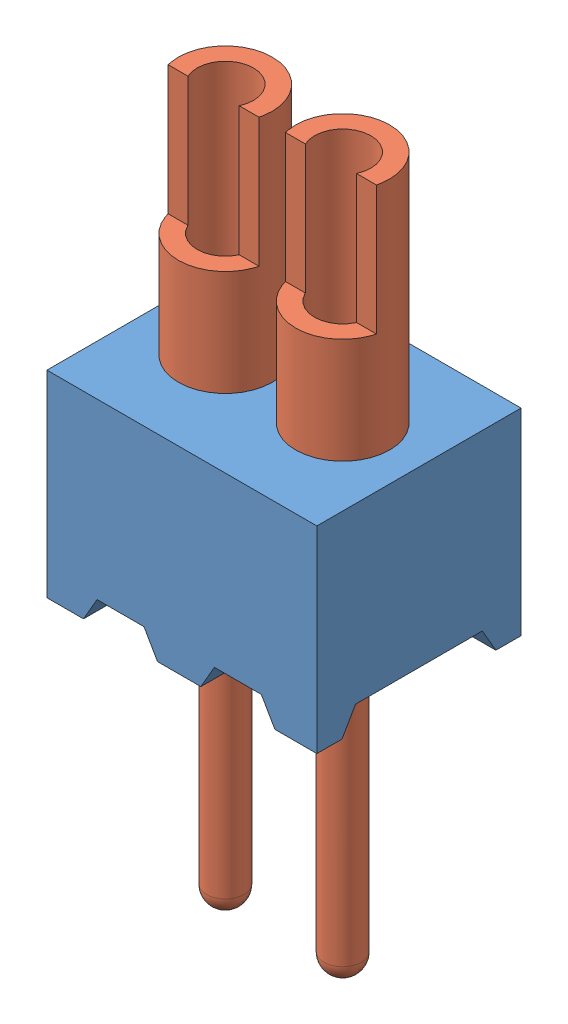
SolidWorks assembly mill-max-850-10-002-10-003000, configuration Default. Lengths in mm.
Overall size (2.92 7.7 2.21).
3 component instances, 2 part files, 0 mates.
Components (placement in the parent):
- mill-max-850-10-002-10-003000_P8XX-18-011-02-000000(P802-18-011-02-000000)-1: mill-max-850-10-002-10-003000_P8XX-18-011-02-000000(P802-18-011-02-000000) [Default] at origin size (2.92 2.13 2.21)
- mill-max-850-10-002-10-003000_3050(3050-0-01-15-00-00-03-0)-1: mill-max-850-10-002-10-003000_3050(3050-0-01-15-00-00-03-0) [Default] at (0.8255 2.54 -1.1049) x (0 -1 0) z (-1 0 0) size (7.7 1.02 1.02)
- mill-max-850-10-002-10-003000_3050(3050-0-01-15-00-00-03-0)-2: mill-max-850-10-002-10-003000_3050(3050-0-01-15-00-00-03-0) [Default] at (2.0955 2.54 -1.1049) x (0 -1 0) z (-1 0 0) size (7.7 1.02 1.02)
